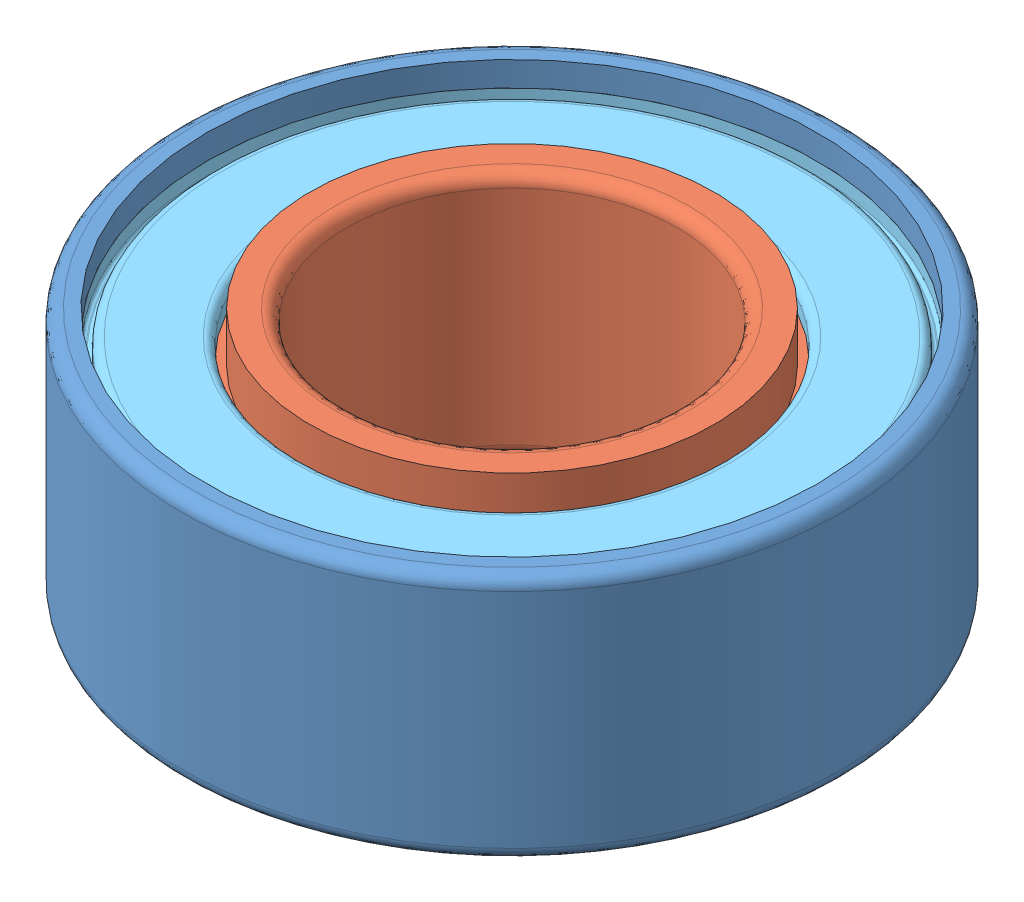
SolidWorks assembly Bearing 8x4x3 Shield, configuration Predeterminado. Lengths in mm.
Overall size (10.75 3 10.75).
15 component instances, 5 part files, 18 mates.
Components (placement in the parent):
- Outer Ring 4x8x3-1: Outer Ring 4x8x3 [Predeterminado] at (2.0057 0.0457 8) size (8 3 8)
- Inner Ring 4x8x3-1: Inner Ring 4x8x3 [Predeterminado] at (2.0057 0.0457 8) x (0.277688 0 -0.960671) z (0.960671 0 0.277688) size (5.2 3 5.2)
- Retainer 4x8x3-1: Retainer 4x8x3 [Predeterminado] at (2.0057 -0.6543 8) x (-0.304608 0 -0.952478) z (0.952478 0 -0.304608) size (6.4 1.4 6.4)
- Ball D1-1: Ball D1 [Predeterminado] at (-0.8518 0.0457 8.9138) size (1 1 1)
- Ball D1-2: Ball D1 [Predeterminado] at (-0.8432 0.0457 7.0597) size (1 1 1)
- Ball D1-3: Ball D1 [Predeterminado] at (2.0196 0.0457 5) size (1 1 1)
- Ball D1-4: Ball D1 [Predeterminado] at (1.9918 0.0457 11) size (1 1 1)
- Ball D1-5: Ball D1 [Predeterminado] at (0.2536 0.0457 5.5648) size (1 1 1)
- Ball D1-6: Ball D1 [Predeterminado] at (3.7578 0.0457 10.4352) size (1 1 1)
- Ball D1-7: Ball D1 [Predeterminado] at (4.8631 0.0457 7.0862) size (1 1 1)
- Ball D1-8: Ball D1 [Predeterminado] at (4.8545 0.0457 8.9403) size (1 1 1)
- Ball D1-9: Ball D1 [Predeterminado] at (3.7803 0.0457 5.5811) size (1 1 1)
- Ball D1-10: Ball D1 [Predeterminado] at (0.2311 0.0457 10.4189) x (0.999036 0.038175 0.021685) z (-0.0227 0.026362 0.999395) size (1 1 1)
- Shield 4x8x3-1: Shield 4x8x3 [Predeterminado] at (-1.5221 -1.1543 9.4123) x (0.928367 0 -0.371664) z (0.371664 0 0.928367) size (7.6 0.3 7.6)
- Shield 4x8x3-2: Shield 4x8x3 [Predeterminado] at (-0.6804 1.2457 10.6879) x (0.706873 0 -0.707341) z (-0.707341 0 -0.706873) size (7.6 0.3 7.6)
Mates (geometry in assembly coordinates):
- Concéntrica1: concentric aligned: cylinder of Outer Ring 4x8x3-1 through (2.0057 1.5457 8) axis (0 1 0) radius 4; cylinder of Inner Ring 4x8x3-1 through (2.0057 1.5457 8) axis (0 1 0) radius 2
- Coincidente1: coincident aligned: plane of Outer Ring 4x8x3-1 through (-1.9943 1.5457 8) normal (0 1 0); plane of Inner Ring 4x8x3-1 through (1.4503 1.5457 9.9213) normal (0 1 0)
- Concéntrica2: concentric anti-aligned: cylinder of Outer Ring 4x8x3-1 through (2.0057 1.5457 8) axis (0 1 0) radius 4; cylinder of Retainer 4x8x3-1 through (2.0057 0.7457 8) axis (0 -1 0) radius 3.2
- Concéntrica3: concentric: sphere of Retainer 4x8x3-1; sphere of Ball D1-10
- Concéntrica4: concentric: sphere of Retainer 4x8x3-1; sphere of Ball D1-1
- Concéntrica5: concentric: sphere of Retainer 4x8x3-1; sphere of Ball D1-2
- Concéntrica6: concentric: sphere of Retainer 4x8x3-1; sphere of Ball D1-5
- Concéntrica7: concentric: sphere of Retainer 4x8x3-1; sphere of Ball D1-3
- Concéntrica8: concentric: sphere of Retainer 4x8x3-1; sphere of Ball D1-9
- Concéntrica9: concentric: sphere of Retainer 4x8x3-1; sphere of Ball D1-4
- Concéntrica10: concentric: sphere of Retainer 4x8x3-1; sphere of Ball D1-7
- Concéntrica11: concentric: sphere of Retainer 4x8x3-1; sphere of Ball D1-6
- Concéntrica12: concentric: sphere of Retainer 4x8x3-1; sphere of Ball D1-8
- Tangente3: tangent: torus of Outer Ring 4x8x3-1; sphere of Ball D1-10
- Concéntrica13: concentric aligned: cylinder of Outer Ring 4x8x3-1 through (2.0057 1.5457 8) axis (0 1 0) radius 3.7; cylinder of Shield 4x8x3-2 through (2.0057 1.2457 8) axis (0 1 0) radius 3.8
- Coincidente2: coincident anti-aligned: plane of Outer Ring 4x8x3-1 through (-1.7943 0.9457 8) normal (0 1 0); plane of Shield 4x8x3-2 through (-0.6098 0.9457 10.6172) normal (0 -1 0)
- Concéntrica14: concentric anti-aligned: cylinder of Outer Ring 4x8x3-1 through (2.0057 1.5457 8) axis (0 1 0) radius 3.8; cylinder of Shield 4x8x3-1 through (2.0057 -1.1543 8) axis (0 -1 0) radius 3.8
- Coincidente3: coincident anti-aligned: plane of Outer Ring 4x8x3-1 through (-1.7943 -0.8543 8) normal (0 -1 0); plane of Shield 4x8x3-1 through (-1.4293 -0.8543 9.3752) normal (0 1 0)
